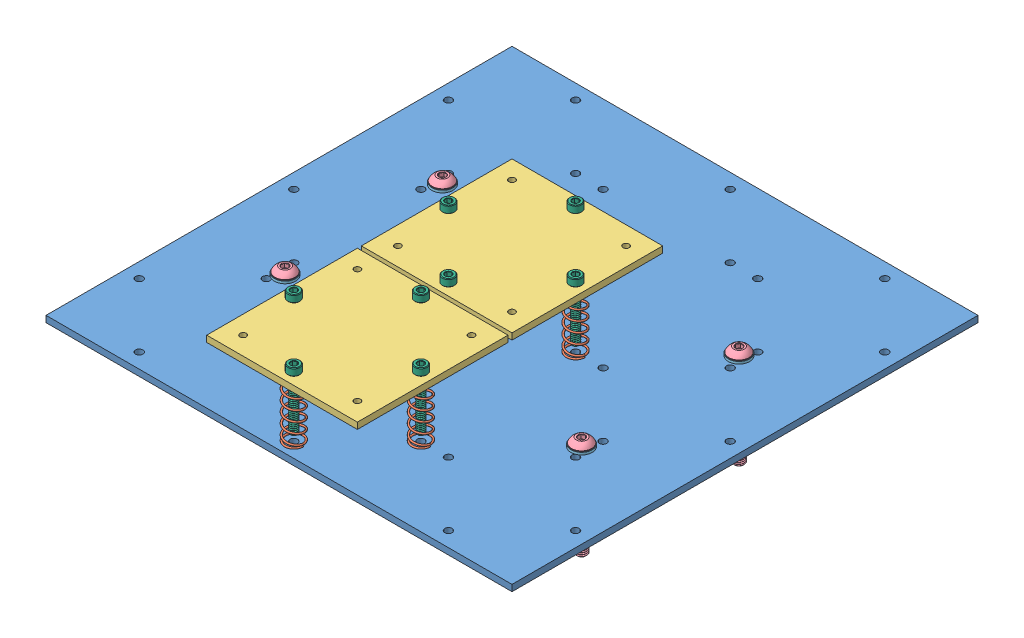
SolidWorks assembly Stage Plate Assembly, configuration Default. Lengths in mm.
Overall size (220 76.32 220).
35 component instances, 8 part files, 69 mates.
Components (placement in the parent):
- Large Stage Plate-1: Large Stage Plate [Default] at origin size (220 3 220)
- Spring-1: Spring [9657K304] at (0 3 43) x (1 0 0) z (0 -1 0) size (9.41 9.52 25.81)
- Spring-2: Spring [9657K304] at (-30 3 73) x (0.91117 0 0.412031) z (0 -1 0) size (9.41 9.52 25.81)
- Spring-3: Spring [9657K304] at (30 3 73) x (1 0 0) z (0 -1 0) size (9.41 9.52 25.81)
- Spring-4: Spring [9657K304] at (0 3 103) x (1 0 0) z (0 -1 0) size (9.41 9.52 25.81)
- Spring-5: Spring [9657K304] at (0 3 -30) x (0.601431 0 -0.798925) z (0 -1 0) size (9.41 9.52 25.81)
- Spring-6: Spring [9657K304] at (30 3 0) x (1 0 0) z (0 -1 0) size (9.41 9.52 25.81)
- Spring-7: Spring [9657K304] at (-30 3 0) x (1 0 0) z (0 -1 0) size (9.41 9.52 25.81)
- Spring-8: Spring [9657K304] at (0 3 30) x (1 0 0) z (0 -1 0) size (9.41 9.52 25.81)
- Small Stage Plate-1: Small Stage Plate [Default] at (0 28.4 0) size (71.12 3 71.12)
- Small Stage Plate-2: Small Stage Plate [Default] at (0 28.4 73) x (0 0 -1) z (1 0 0) size (71.12 3 71.12)
- M5 Bolt-1: M5 Bolt [91239A244] at (-70 6.85 37.15) x (0.614988 0 -0.788537) z (0 1 0) size (9.5 9.5 48.28)
- M5 Bolt-2: M5 Bolt [91239A244] at (70 6.85 -37.15) x (0.071032 0 -0.997474) z (0 1 0) size (9.5 9.5 48.28)
- M5 Bolt-3: M5 Bolt [91239A244] at (-70 6.85 -37.15) x (-0.018819 0 0.999823) z (0 1 0) size (9.5 9.5 48.28)
- M5 Bolt-4: M5 Bolt [91239A244] at (70 6.85 37.15) x (0.993045 0 0.117733) z (0 1 0) size (9.5 9.5 48.28)
- M5 Washer-1: M5 Washer [90965A160] at (70 4.1 -37.15) x (0.738011 0 -0.674788) z (0 -1 0) size (10 10 1.1)
- M5 Washer-2: M5 Washer [90965A160] at (-70 4.1 37.15) x (0.993945 0 0.109875) z (0 -1 0) size (10 10 1.1)
- M5 Washer-3: M5 Washer [90965A160] at (70 4.1 37.15) x (1 0 0) z (0 -1 0) size (10 10 1.1)
- M5 Washer-4: M5 Washer [90965A160] at (-70 4.1 -37.15) x (0.473855 0 -0.880603) z (0 -1 0) size (10 10 1.1)
- 6-32 Bolt-4: 6-32 Bolt [92185A156] at (-30 6 73) x (0.554935 0 -0.831894) z (0 -1 0) size (5.74 5.74 29.34)
- 6-32 Bolt-5: 6-32 Bolt [92185A156] at (0 6 103) x (1 0 0) z (0 -1 0) size (5.74 5.74 29.34)
- 6-32 Bolt-6: 6-32 Bolt [92185A156] at (30 6 73) x (0.448928 0 -0.893568) z (0 -1 0) size (5.74 5.74 29.34)
- 6-32 Bolt-7: 6-32 Bolt [92185A156] at (0 6 30) x (1 0 0) z (0 -1 0) size (5.74 5.74 29.34)
- 6-32 Bolt-8: 6-32 Bolt [92185A156] at (0 6 -30) x (-0.544263 0 0.838915) z (0 -1 0) size (5.74 5.74 29.34)
- 6-32 Bolt-9: 6-32 Bolt [92185A156] at (30 6 0) x (0.273801 0 0.961786) z (0 -1 0) size (5.74 5.74 29.34)
- 6-32 Bolt-10: 6-32 Bolt [92185A156] at (0 6 43) x (0.993838 0 -0.110845) z (0 -1 0) size (5.74 5.74 29.34)
- 6-32 Bolt-11: 6-32 Bolt [92185A156] at (-30 6 0) x (0.42203 0 -0.906582) z (0 -1 0) size (5.74 5.74 29.34)
- Spacer-1: Spacer [92871A227] at (-70 -15 -37.15) x (-0.858027 0 -0.513604) z (0 -1 0) size (10 10 30)
- Spacer-2: Spacer [92871A227] at (70 -15 37.15) x (-0.906194 0 0.422863) z (0 -1 0) size (10 10 30)
- Spacer-3: Spacer [92871A227] at (-70 -15 37.15) x (0.67961 0 -0.733574) z (0 -1 0) size (10 10 30)
- Spacer-4: Spacer [92871A227] at (70 -15 -37.15) x (-0.824326 0 0.566116) z (0 -1 0) size (10 10 30)
- M5 Nut-5: M5 Nut [90592A012] at (70 -32 -37.15) x (-0.926218 0 -0.376988) z (0 -1 0) size (8 9.24 4.46)
- M5 Nut-6: M5 Nut [90592A012] at (-70 -32 37.15) x (1 0 0) z (0 -1 0) size (8 9.24 4.46)
- M5 Nut-7: M5 Nut [90592A012] at (70 -32 37.15) x (0.420485 0 0.9073) z (0 -1 0) size (8 9.24 4.46)
- M5 Nut-8: M5 Nut [90592A012] at (-70 -32 -37.15) x (-0.843032 0 0.537863) z (0 -1 0) size (8 9.24 4.46)
Mates (geometry in assembly coordinates):
- Coincident1: coincident anti-aligned: plane of Large Stage Plate-1 through (0 3 0) normal (0 1 0); plane of Spring-4 through (0 3 103) normal (0 -1 0)
- Coincident2: coincident anti-aligned: plane of Large Stage Plate-1 through (0 3 0) normal (0 1 0); plane of Spring-2 through (-30 3 73) normal (0 -1 0)
- Coincident3: coincident anti-aligned: plane of Large Stage Plate-1 through (0 3 0) normal (0 1 0); plane of Spring-3 through (30 3 73) normal (0 -1 0)
- Coincident4: coincident anti-aligned: plane of Large Stage Plate-1 through (0 3 0) normal (0 1 0); plane of Spring-1 through (0 3 43) normal (0 -1 0)
- Coincident5: coincident anti-aligned: plane of Large Stage Plate-1 through (0 3 0) normal (0 1 0); plane of Spring-6 through (30 3 0) normal (0 -1 0)
- Coincident6: coincident anti-aligned: plane of Large Stage Plate-1 through (0 3 0) normal (0 1 0); plane of Spring-8 through (0 3 30) normal (0 -1 0)
- Coincident7: coincident anti-aligned: plane of Large Stage Plate-1 through (0 3 0) normal (0 1 0); plane of Spring-7 through (-30 3 0) normal (0 -1 0)
- Coincident8: coincident anti-aligned: plane of Large Stage Plate-1 through (0 3 0) normal (0 1 0); plane of Spring-5 through (0 3 -30) normal (0 -1 0)
- Coincident26: coincident anti-aligned: plane of Spring-5 through (0 28.4 -30) normal (0 1 0); plane of Small Stage Plate-1 through (0 28.4 0) normal (0 -1 0)
- Coincident27: coincident anti-aligned: plane of Spring-4 through (0 28.4 103) normal (0 1 0); plane of Small Stage Plate-2 through (0 28.4 73) normal (0 -1 0)
- Concentric17: concentric anti-aligned: circle of M5 Washer-1; circle of Large Stage Plate-1
- Coincident43: coincident anti-aligned: plane of Large Stage Plate-1 through (0 3 0) normal (0 1 0); plane of M5 Washer-1 through (70 3 -37.15) normal (0 -1 0)
- Concentric18: concentric anti-aligned: circle of M5 Washer-3; circle of Large Stage Plate-1
- Coincident45: coincident anti-aligned: plane of Large Stage Plate-1 through (0 3 0) normal (0 1 0); plane of M5 Washer-3 through (70 3 37.15) normal (0 -1 0)
- Concentric19: concentric anti-aligned: circle of M5 Washer-4; circle of Large Stage Plate-1
- Coincident47: coincident anti-aligned: plane of Large Stage Plate-1 through (0 3 0) normal (0 1 0); plane of M5 Washer-4 through (-70 3 -37.15) normal (0 -1 0)
- Concentric20: concentric anti-aligned: circle of M5 Washer-2; circle of Large Stage Plate-1
- Coincident49: coincident anti-aligned: plane of Large Stage Plate-1 through (0 3 0) normal (0 1 0); plane of M5 Washer-2 through (-70 3 37.15) normal (0 -1 0)
- Coincident56: coincident anti-aligned: plane of Small Stage Plate-1 through (0 31.4 0) normal (0 1 0); plane of 6-32 Bolt-8 through (0 31.4 -30) normal (0 -1 0)
- Coincident57: coincident anti-aligned: plane of Small Stage Plate-1 through (0 31.4 0) normal (0 1 0); plane of 6-32 Bolt-9 through (30 31.4 0) normal (0 -1 0)
- Coincident58: coincident anti-aligned: plane of Small Stage Plate-1 through (0 31.4 0) normal (0 1 0); plane of 6-32 Bolt-7 through (0 31.4 30) normal (0 -1 0)
- Coincident59: coincident anti-aligned: plane of Small Stage Plate-1 through (0 31.4 0) normal (0 1 0); plane of 6-32 Bolt-11 through (-30 31.4 0) normal (0 -1 0)
- Coincident61: coincident anti-aligned: plane of Small Stage Plate-2 through (0 31.4 73) normal (0 1 0); plane of 6-32 Bolt-6 through (30 31.4 73) normal (0 -1 0)
- Coincident62: coincident anti-aligned: plane of Small Stage Plate-2 through (0 31.4 73) normal (0 1 0); plane of 6-32 Bolt-5 through (0 31.4 103) normal (0 -1 0)
- Coincident63: coincident anti-aligned: plane of Small Stage Plate-2 through (0 31.4 73) normal (0 1 0); plane of 6-32 Bolt-4 through (-30 31.4 73) normal (0 -1 0)
- Coincident64: coincident anti-aligned: plane of Small Stage Plate-2 through (0 31.4 73) normal (0 1 0); plane of 6-32 Bolt-10 through (0 31.4 43) normal (0 -1 0)
- Concentric35: concentric anti-aligned: circle of Spacer-1; circle of Large Stage Plate-1
- Concentric36: concentric anti-aligned: circle of Spacer-2; circle of Large Stage Plate-1
- Concentric37: concentric anti-aligned: circle of Spacer-3; circle of Large Stage Plate-1
- Coincident65: coincident anti-aligned: plane of Large Stage Plate-1 through (0 0 0) normal (0 -1 0); plane of Spacer-1 through (-70 0 -37.15) normal (0 1 0)
- Coincident66: coincident anti-aligned: plane of Large Stage Plate-1 through (0 0 0) normal (0 -1 0); plane of Spacer-2 through (70 0 37.15) normal (0 1 0)
- Coincident67: coincident anti-aligned: plane of Large Stage Plate-1 through (0 0 0) normal (0 -1 0); plane of Spacer-4 through (70 0 -37.15) normal (0 1 0)
- Coincident68: coincident anti-aligned: plane of Large Stage Plate-1 through (0 0 0) normal (0 -1 0); plane of Spacer-3 through (-70 0 37.15) normal (0 1 0)
- Concentric39: concentric anti-aligned: circle of Spacer-4; circle of M5 Nut-5
- Coincident69: coincident anti-aligned: plane of Spacer-4 through (70 -30 -37.15) normal (0 -1 0); plane of M5 Nut-5 through (74.5755 -30 -37.7811) normal (0 1 0)
- Concentric41: concentric anti-aligned: circle of Spacer-3; circle of M5 Nut-6
- Coincident70: coincident anti-aligned: plane of Spacer-3 through (-70 -30 37.15) normal (0 -1 0); plane of M5 Nut-6 through (-74 -30 39.4594) normal (0 1 0)
- Concentric42: concentric anti-aligned: circle of Spacer-2; circle of M5 Nut-7
- Coincident71: coincident anti-aligned: plane of Spacer-2 through (70 -30 37.15) normal (0 -1 0); plane of M5 Nut-7 through (66.2227 -30 34.4919) normal (0 1 0)
- Concentric43: concentric anti-aligned: circle of Spacer-1; circle of M5 Nut-8
- Coincident72: coincident anti-aligned: plane of Spacer-1 through (-70 -30 -37.15) normal (0 -1 0); plane of M5 Nut-8 through (-67.87 -30 -41.2484) normal (0 1 0)
- Concentric44: concentric aligned: circle of M5 Bolt-2; circle of M5 Washer-1
- Coincident73: coincident anti-aligned: plane of M5 Bolt-2 through (74.738 4.1 -36.8126) normal (0 -1 0); plane of M5 Washer-1 through (70 4.1 -37.15) normal (0 1 0)
- Concentric45: concentric aligned: circle of M5 Bolt-4; circle of M5 Washer-3
- Coincident74: coincident aligned: plane of M5 Bolt-4 through (69.4408 4.1 41.867) normal (0 -1 0); circle of M5 Washer-3
- Concentric46: concentric aligned: circle of M5 Bolt-3; circle of M5 Washer-4
- Coincident75: coincident anti-aligned: plane of M5 Bolt-3 through (-74.7492 4.1 -37.2394) normal (0 -1 0); plane of M5 Washer-4 through (-70 4.1 -37.15) normal (0 1 0)
- Concentric47: concentric aligned: circle of M5 Bolt-1; circle of M5 Washer-2
- Coincident76: coincident anti-aligned: plane of M5 Bolt-1 through (-66.2545 4.1 40.0712) normal (0 -1 0); plane of M5 Washer-2 through (-70 4.1 37.15) normal (0 1 0)
- Coincident77: coincident: point of Large Stage Plate-1; point of Spring-1
- Coincident78: coincident: point of Large Stage Plate-1; point of Spring-2
- Coincident79: coincident: point of Large Stage Plate-1; point of Spring-3
- Coincident80: coincident: point of Large Stage Plate-1; point of Spring-5
- Coincident82: coincident: point of Large Stage Plate-1; point of Spring-6
- Coincident83: coincident: point of Large Stage Plate-1; point of Spring-7
- Coincident84: coincident: point of Large Stage Plate-1; point of Spring-8
- Concentric48: concentric anti-aligned: circle of Large Stage Plate-1; circle of 6-32 Bolt-5
- Concentric49: concentric anti-aligned: circle of Large Stage Plate-1; circle of 6-32 Bolt-4
- Concentric50: concentric anti-aligned: circle of Large Stage Plate-1; circle of 6-32 Bolt-6
- Concentric51: concentric anti-aligned: circle of Large Stage Plate-1; circle of 6-32 Bolt-10
- Concentric53: concentric anti-aligned: circle of Large Stage Plate-1; circle of 6-32 Bolt-7
- Concentric54: concentric anti-aligned: circle of Large Stage Plate-1; circle of 6-32 Bolt-11
- Concentric55: concentric anti-aligned: circle of Large Stage Plate-1; circle of 6-32 Bolt-8
- Concentric56: concentric anti-aligned: circle of Large Stage Plate-1; circle of 6-32 Bolt-9
- Concentric57: concentric aligned: circle of Large Stage Plate-1; circle of Small Stage Plate-2
- Concentric58: concentric aligned: circle of Large Stage Plate-1; circle of Small Stage Plate-2
- Concentric59: concentric aligned: circle of Large Stage Plate-1; circle of Small Stage Plate-1
- Concentric60: concentric aligned: circle of Large Stage Plate-1; circle of Small Stage Plate-1
- Concentric61: concentric anti-aligned: circle of Large Stage Plate-1; circle of Spacer-4
